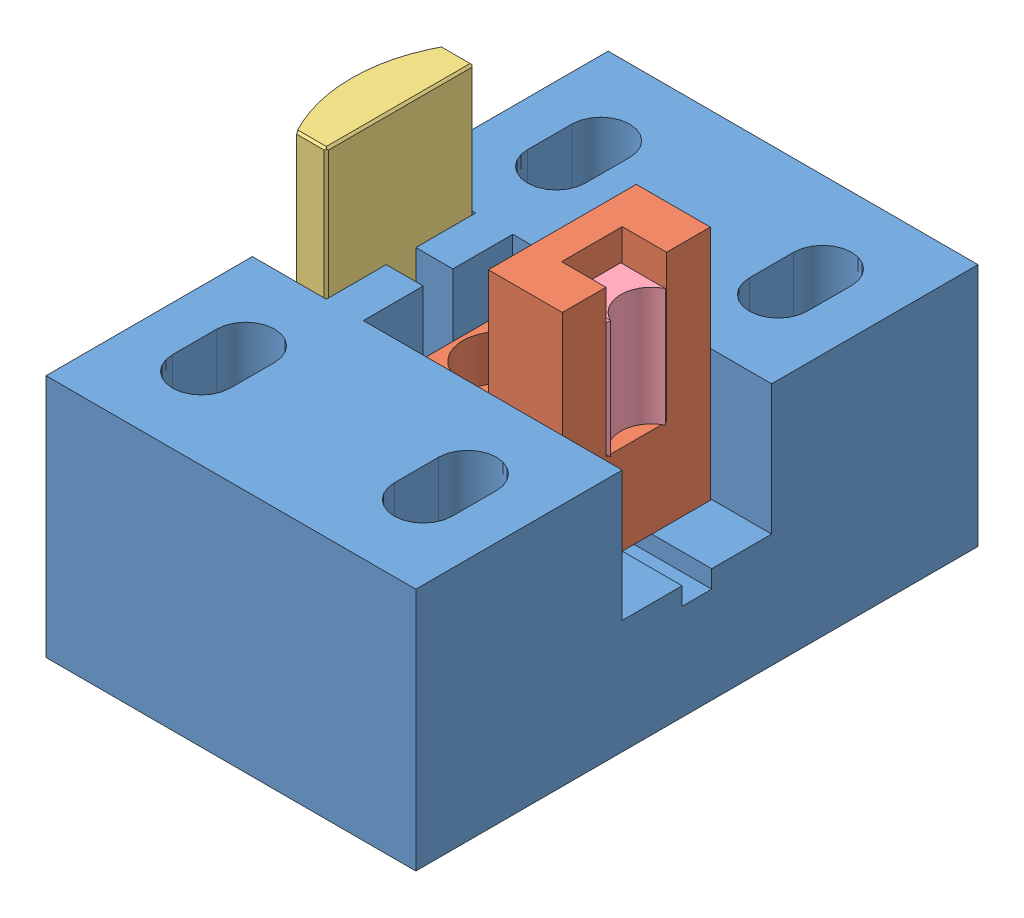
SolidWorks assembly telescope_v2_two_part, configuration Default. Lengths in mm.
Overall size (25 25.3 38).
4 component instances, 4 part files, 9 mates.
Components (placement in the parent):
- telescope_v2_concave-2: telescope_v2_concave [Default] at (18505.0278 17.5357 11312.7564) size (25 16.5 38)
- telescope_lens_plate-1: telescope_lens_plate [Default] at (32.0332 32.257 13.9502) x (-1 0 0) z (0 0 -1) size (12 16 10) (hidden)
- cylindricalconvex_LJ1960L1-B-Solidworks-1: cylindricalconvex_LJ1960L1-B-Solidworks [Default] at (14.4361 36.8357 14.6151) x (0 1 0) z (-1 0 0) size (12 10 3.29)
- cyl_lens_concave-2: cyl_lens_concave [Default] at (30.6125 35.3109 14.6651) x (0 1 0) z (1 0 0) size (8 4 3.16)
Mates (geometry in assembly coordinates):
- Coincident1: coincident anti-aligned: plane of telescope_v2_concave-1 through (10 -12.48 0) normal (0 -1 0); plane of telescope_v2_convex-1 through (0.1643 -12.48 -14.8816) normal (0 1 0)
- Coincident2: coincident anti-aligned: plane of telescope_v2_concave-2 through (18505.0278 30.8357 11312.7564) normal (0 1 0); plane of cylindricalconvex_LJ1960L1-B-Solidworks-1 through (23.1311 30.8357 14.6151) normal (0 -1 0)
- Coincident3: coincident anti-aligned: plane of telescope_v2_concave-2 through (16.0811 6.2659 11312.7564) normal (-1 0 0); plane of cylindricalconvex_LJ1960L1-B-Solidworks-1 through (16.0811 42.8357 9.6151) normal (1 0 0)
- Coincident4: coincident anti-aligned: plane of telescope_v2_concave-2 through (18505.0278 6.2659 19.6151) normal (0 0 -1); plane of cylindricalconvex_LJ1960L1-B-Solidworks-1 through (16.0811 42.8357 19.6151) normal (0 0 1)
- Coincident7: coincident anti-aligned: plane of telescope_v2_concave-2 through (36.0811 25.2357 19.6151) normal (0 0 -1); plane of telescope_lens_plate-1 through (20.0332 41.2357 19.6151) normal (0 0 1)
- Coincident8: coincident anti-aligned: plane of telescope_v2_concave-2 through (18505.0278 25.2357 11312.7564) normal (0 1 0); plane of telescope_lens_plate-1 through (20.0332 25.2357 9.6151) normal (0 -1 0)
- Coincident9: coincident anti-aligned: plane of telescope_lens_plate-1 through (29.0332 32.257 13.9502) normal (1 0 0); plane of cyl_lens_concave-2 through (29.0332 39.3109 16.6651) normal (-1 0 0)
- Coincident10: coincident anti-aligned: plane of telescope_lens_plate-1 through (29.0332 31.3109 13.9502) normal (0 1 0); plane of cyl_lens_concave-2 through (33.1032 31.3109 14.6651) normal (0 -1 0)
- Coincident11: coincident anti-aligned: plane of telescope_lens_plate-1 through (20.0332 32.257 16.6651) normal (0 0 -1); plane of cyl_lens_concave-2 through (32.5694 39.3109 16.6651) normal (0 0 1)
